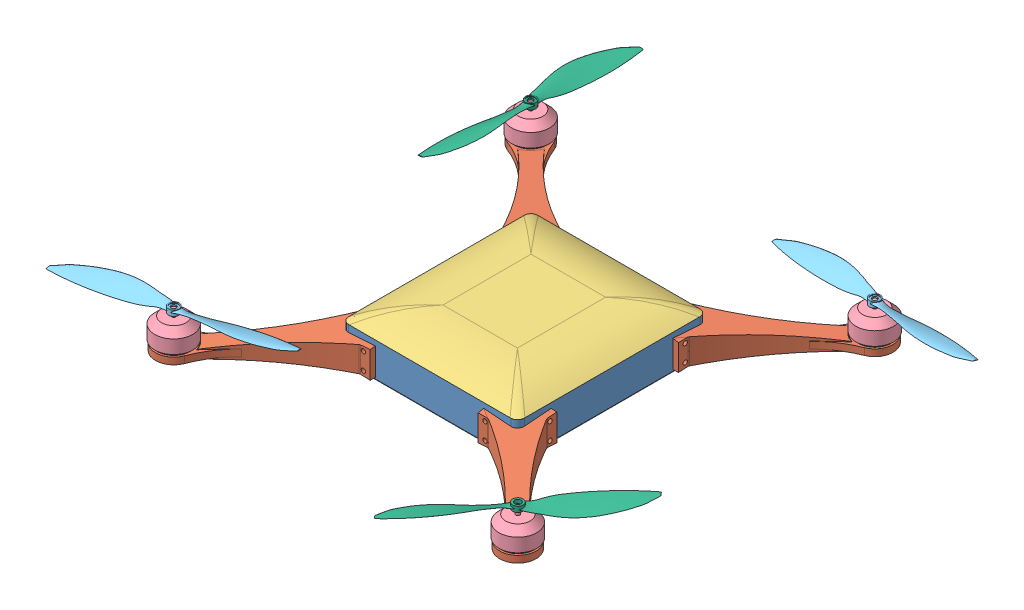
SolidWorks assembly Assem2, configuration Default. Lengths in mm.
Overall size (404.99 41.96 401.58).
14 component instances, 6 part files, 31 mates.
Components (placement in the parent):
- base2.1-1: base2.1 [Default] at (14.0455 -10.7511 -30.1953) size (130.1 30.08 140.13)
- kanat0.2-1: kanat0.2 [Default] at (161.1794 -4.5011 310.6072) size (100.86 20.03 100.61)
- kanat0.2-2: kanat0.2 [Default] at (301.4492 -4.5011 -171.244) x (0 0 -1) z (1 0 0) size (100.86 20.03 100.61)
- kanat0.2-3: kanat0.2 [Default] at (-170.4019 -4.5011 -311.5138) x (-1 0 0) z (0 0 -1) size (100.86 20.03 100.61)
- kanat0.2-4: kanat0.2 [Default] at (-310.6718 -4.5011 170.3373) x (0 0 1) z (-1 0 0) size (100.86 20.03 100.61)
- kapak0-1: kapak0 [Default] at (-7.7379 19.2489 -12.0717) x (0 0 -1) z (1 0 0) size (140.74 10 130.74)
- brushless-1: brushless [Default] at (-131.9668 5.4989 -132.5437) x (0.694987 0 0.719022) z (-0.719022 0 0.694987) size (28 22 28)
- brushless-2: brushless [Default] at (122.4791 5.4989 -132.8088) x (0.719022 0 -0.694987) z (0.694987 0 0.719022) size (28 22 28)
- brushless-3: brushless [Default] at (122.7442 5.4989 131.6371) x (0.694987 0 0.719022) z (-0.719022 0 0.694987) size (28 22 28)
- brushless-4: brushless [Default] at (-131.7017 5.4989 131.9022) x (0.719022 0 -0.694987) z (0.694987 0 0.719022) size (28 22 28)
- 6x3-clockwise-propeller-1: 6x3-clockwise-propeller [Default] at (117.6203 23.0416 -128.8299) x (0.232603 0 -0.972572) z (0.972572 0 0.232603) size (36.02 6.32 147.86)
- 6x3-clockwise-propeller-2: 6x3-clockwise-propeller [Default] at (-128.1505 23.0416 126.7225) x (0.048864 0 0.998805) z (-0.998805 0 0.048864) size (36.02 6.32 147.86)
- 6x3-counterclockwise-propeller-1: 6x3-counterclockwise-propeller [Default] at (116.6075 31.9536 130.3026) x (0.649406 0 0.760442) z (0.760442 0 -0.649406) size (36.02 6.32 147.86)
- 6x3-counterclockwise-propeller-2: 6x3-counterclockwise-propeller [Default] at (-126.4968 23.0442 -129.4584) x (-0.990726 0 0.135878) z (-0.135878 0 -0.990726) size (36.02 6.32 147.86)
Mates (geometry in assembly coordinates):
- Coincident9: coincident anti-aligned: plane of base2.1-1 through (-69.6113 -0.7511 -70.4533) normal (0 0 -1); plane of kanat0.2-3 through (-44.6113 15.4989 -70.4533) normal (0 0 1)
- Coincident10: coincident anti-aligned: plane of base2.1-1 through (-69.6113 -0.7511 -70.4533) normal (-1 0 0); plane of kanat0.2-3 through (-69.6113 15.4989 -70.4533) normal (1 0 0)
- Coincident11: coincident anti-aligned: plane of base2.1-1 through (60.3887 -0.7511 -70.4533) normal (1 0 0); plane of kanat0.2-2 through (60.3887 15.4989 -45.4533) normal (-1 0 0)
- Coincident12: coincident anti-aligned: plane of base2.1-1 through (-69.6113 -0.7511 -70.4533) normal (0 0 -1); plane of kanat0.2-2 through (60.3887 15.4989 -70.4533) normal (0 0 1)
- Coincident13: coincident anti-aligned: plane of base2.1-1 through (60.3887 -0.7511 -70.4533) normal (1 0 0); plane of kanat0.2-1 through (60.3887 15.4989 69.5467) normal (-1 0 0)
- Coincident14: coincident anti-aligned: plane of base2.1-1 through (-69.6113 -0.7511 69.5467) normal (0 0 1); plane of kanat0.2-1 through (35.3887 15.4989 69.5467) normal (0 0 -1)
- Coincident15: coincident anti-aligned: plane of base2.1-1 through (-69.6113 -0.7511 69.5467) normal (0 0 1); plane of kanat0.2-4 through (-69.6113 15.4989 69.5467) normal (0 0 -1)
- Coincident16: coincident anti-aligned: plane of base2.1-1 through (-69.6113 -0.7511 -70.4533) normal (-1 0 0); plane of kanat0.2-4 through (-69.6113 15.4989 44.5467) normal (1 0 0)
- Concentric1: concentric anti-aligned: circle of base2.1-1; circle of kanat0.2-1
- Concentric2: concentric anti-aligned: circle of base2.1-1; circle of kanat0.2-2
- Concentric3: concentric anti-aligned: circle of base2.1-1; circle of kanat0.2-3
- Concentric4: concentric anti-aligned: circle of base2.1-1; circle of kanat0.2-4
- Coincident17: coincident anti-aligned: plane of base2.1-1 through (14.0455 19.2489 -30.1953) normal (0 1 0); plane of kapak0-1 through (-7.7379 19.2489 -12.0717) normal (0 -1 0)
- Coincident18: coincident aligned: line of base2.1-1 through (-69.6113 19.2489 -65.4533) axis (0 0 1); line of kapak0-1 through (-69.6113 19.2489 -64.9656) axis (0 0 1)
- Coincident19: coincident aligned: line of base2.1-1 through (-64.6113 19.2489 69.5467) axis (1 0 0); line of kapak0-1 through (-64.1235 19.2489 69.5467) axis (1 0 0)
- Coincident26: coincident anti-aligned: circle of kanat0.2-2; circle of brushless-2
- Coincident27: coincident anti-aligned: circle of kanat0.2-2; circle of brushless-2
- Coincident28: coincident: circle of kanat0.2-1; circle of brushless-3
- Coincident29: coincident: circle of kanat0.2-1; circle of brushless-3
- Coincident30: coincident anti-aligned: circle of kanat0.2-4; circle of brushless-4
- Coincident31: coincident anti-aligned: circle of kanat0.2-4; circle of brushless-4
- Coincident32: coincident anti-aligned: circle of kanat0.2-3; circle of brushless-1
- Coincident33: coincident anti-aligned: circle of kanat0.2-3; circle of brushless-1
- Concentric5: concentric anti-aligned: circle of brushless-2; circle of 6x3-clockwise-propeller-1
- Coincident34: coincident anti-aligned: plane of brushless-2 through (122.4791 27.4989 -132.8088) normal (0 1 0); plane of 6x3-clockwise-propeller-1 through (122.4791 27.4989 -132.8088) normal (0 -1 0)
- Concentric6: concentric anti-aligned: circle of brushless-4; circle of 6x3-clockwise-propeller-2
- Coincident35: coincident anti-aligned: plane of brushless-4 through (-131.7017 27.4989 131.9022) normal (0 1 0); plane of 6x3-clockwise-propeller-2 through (-131.7017 27.4989 131.9022) normal (0 -1 0)
- Coincident36: coincident anti-aligned: plane of brushless-1 through (-131.9668 27.4989 -132.5437) normal (0 1 0); plane of 6x3-counterclockwise-propeller-2 through (-131.9668 27.4989 -132.5437) normal (0 -1 0)
- Concentric8: concentric anti-aligned: circle of brushless-1; circle of 6x3-counterclockwise-propeller-2
- Concentric9: concentric aligned: circle of brushless-3; circle of 6x3-counterclockwise-propeller-1
- Coincident39: coincident aligned: plane of brushless-3 through (122.7442 27.4989 131.6371) normal (0 1 0); plane of 6x3-counterclockwise-propeller-1 through (122.7442 27.4989 131.6371) normal (0 1 0)
